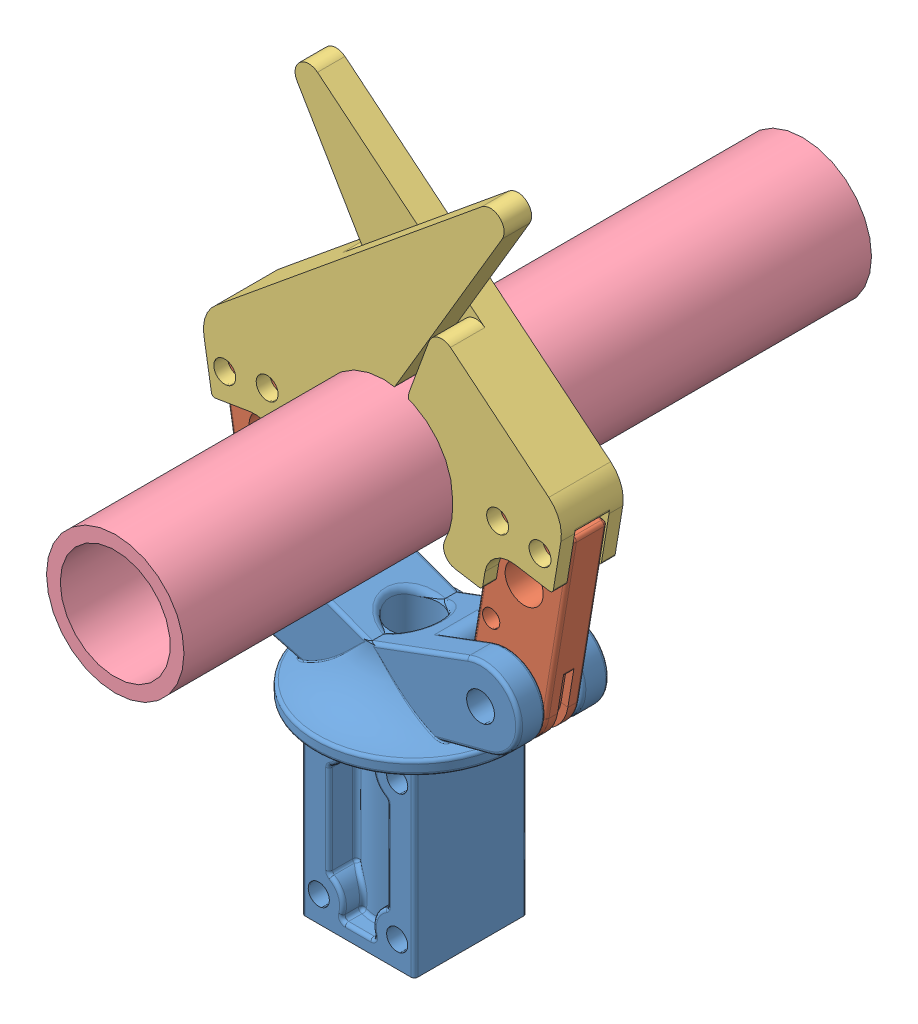
SolidWorks assembly MS-A-0013f-03-02-Center Claw, configuration Default. Lengths in mm.
Overall size (78.21 126.23 127).
6 component instances, 4 part files, 6 mates.
Components (placement in the parent):
- MS-P-0064-03-02 Gripper Center Claw Piece-1: MS-P-0064-03-02 Gripper Center Claw Piece [Default] at (24.6401 45.6335 29.0361) x (0 0 -1) z (1 0 0) size (36.64 54.77 55.37)
- MS-P-0067-03 Gripper Claw Base-2: MS-P-0067-03 Gripper Claw Base [Default] at (4.0978 45.6335 29.2266) x (0.986614 0.163074 0) z (0 0 1) size (14.29 38.89 6.35)
- MS-P-0065-03 Gripper Claw v5-1: MS-P-0065-03 Gripper Claw v5 [Default] at (8.5571 62.461 26.0516) x (0 0 -1) z (0.986614 0.163074 0) size (11.43 54.73 61.98)
- MS-P-0065-03 Gripper Claw v5-3: MS-P-0065-03 Gripper Claw v5 [Default] at (40.723 62.461 32.4016) x (0 0 1) z (-0.986614 0.163074 0) size (11.43 54.73 61.98)
- MS-P-0067-03 Gripper Claw Base-3: MS-P-0067-03 Gripper Claw Base [Default] at (45.1823 45.6335 29.2266) x (-0.986614 0.163074 0) z (0 0 -1) size (14.29 38.89 6.35)
- MS-P-0066-03 PVC Pipe-1: MS-P-0066-03 PVC Pipe [Default] at (24.8977 73.9317 -42.4523) size (25.4 25.4 127)
Mates (geometry in assembly coordinates):
- Coincident3: coincident anti-aligned: plane of MS-P-0064-03-02 Gripper Center Claw Piece-1 through (24.6401 45.6335 32.4016) normal (0 0 -1); plane of MS-P-0067-03 Gripper Claw Base-2 through (4.0978 45.6335 32.4016) normal (0 0 1)
- Concentric3: concentric aligned: circle of MS-P-0064-03-02 Gripper Center Claw Piece-1; circle of MS-P-0067-03 Gripper Claw Base-2
- Concentric5: concentric aligned: circle of MS-P-0067-03 Gripper Claw Base-2; circle of MS-P-0065-03 Gripper Claw v5-1
- Concentric4: concentric aligned: circle of MS-P-0067-03 Gripper Claw Base-2; circle of MS-P-0065-03 Gripper Claw v5-1
- Coincident8: coincident anti-aligned: plane of MS-P-0067-03 Gripper Claw Base-2 through (4.0978 45.6335 26.0516) normal (0 0 -1); plane of MS-P-0065-03 Gripper Claw v5-1 through (8.5571 62.461 26.0516) normal (0 0 1)
- LimitAngle1: limit planar angle = 2.089782 rad anti-aligned: plane of MS-P-0064-03-02 Gripper Center Claw Piece-1 through (6.5821 52.3314 20.7176) normal (0.347759 0.937584 0); plane of MS-P-0067-03 Gripper Claw Base-2 through (11.1459 46.7985 32.4016) normal (0.986614 0.163074 0)
